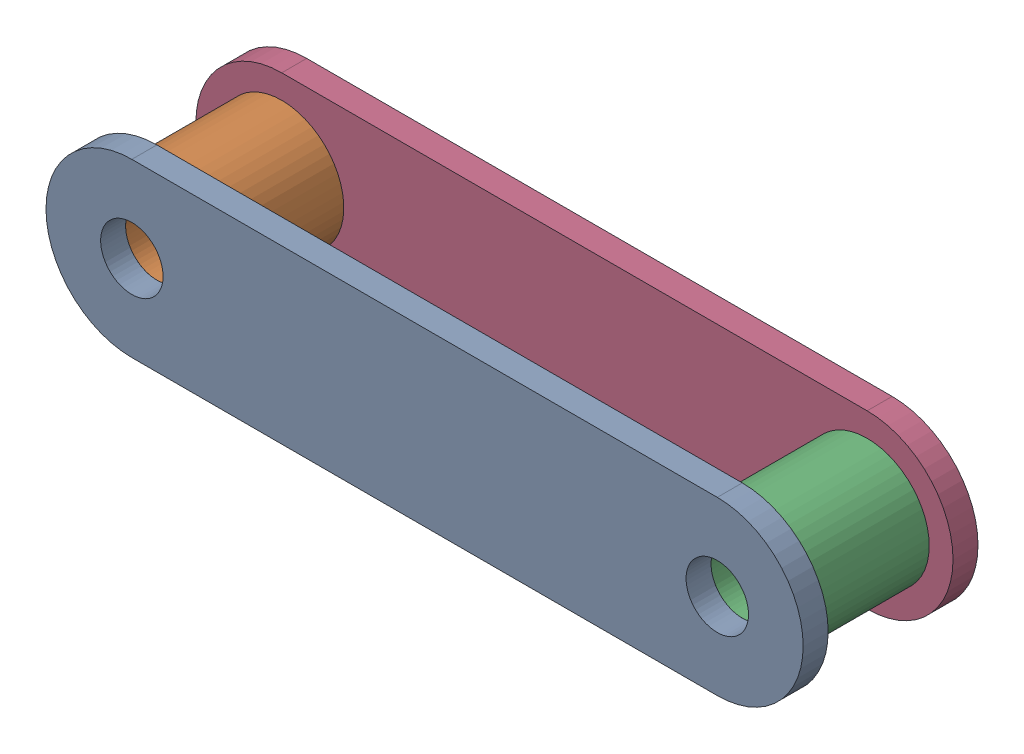
SolidWorks assembly ChainGroup1, configuration Default. Lengths in mm.
Overall size (97 22 22.4).
4 component instances, 2 part files, 10 mates.
Components (placement in the parent):
- Link-1: Link [Default] at (0 0 8) size (97 22 3.2)
- Roller-1: Roller [Default] at (0 0 -8) x (0.99707 0.076499 0) z (0 0 1) size (15.9 15.9 16)
- Roller-2: Roller [Default] at (75 0 -8) x (0.990385 -0.138338 0) z (0 0 1) size (15.9 15.9 16)
- Link-2: Link [Default] at (0 0 -11.2) size (97 22 3.2)
Mates (geometry in assembly coordinates):
- Concentric1: concentric aligned: cylinder of Link-1 through (0 0 11.2) axis (0 0 -1) radius 4; cylinder of Roller-1 through (0 0 8) axis (0 0 -1) radius 7.95
- Concentric2: concentric aligned: cylinder of Link-1 through (75 0 11.2) axis (0 0 -1) radius 4; cylinder of Roller-2 through (75 0 8) axis (0 0 -1) radius 4
- Coincident1: coincident anti-aligned: plane of Link-1 through (0 0 8) normal (0 0 -1); plane of Roller-1 through (0 0 8) normal (0 0 1)
- Coincident2: coincident anti-aligned: plane of Link-1 through (0 0 8) normal (0 0 -1); plane of Roller-2 through (75 0 8) normal (0 0 1)
- Concentric3: concentric aligned: cylinder of Link-1 through (0 0 11.2) axis (0 0 -1) radius 4; cylinder of Link-2 through (0 0 -8) axis (0 0 -1) radius 4
- Concentric4: concentric aligned: cylinder of Link-1 through (75 0 11.2) axis (0 0 -1) radius 4; cylinder of Link-2 through (75 0 -8) axis (0 0 -1) radius 4
- Coincident4: coincident anti-aligned: plane of Roller-1 through (0 0 -8) normal (0 0 -1); plane of Link-2 through (0 0 -8) normal (0 0 1)
- Symmetric2: symmetric aligned: plane of Link-1 through (0 0 8) normal (0 0 -1); plane of Link-2 through (0 0 -8) normal (0 0 1)
- Symmetric4: symmetric aligned: plane of Link-1 through (0 11 11.2) normal (0 1 0); plane of Link-1 through (0 -11 11.2) normal (0 -1 0)
- Concentric5: concentric: cylinder of Roller-1 through (0 0 8) axis (0 0 -1) radius 4
